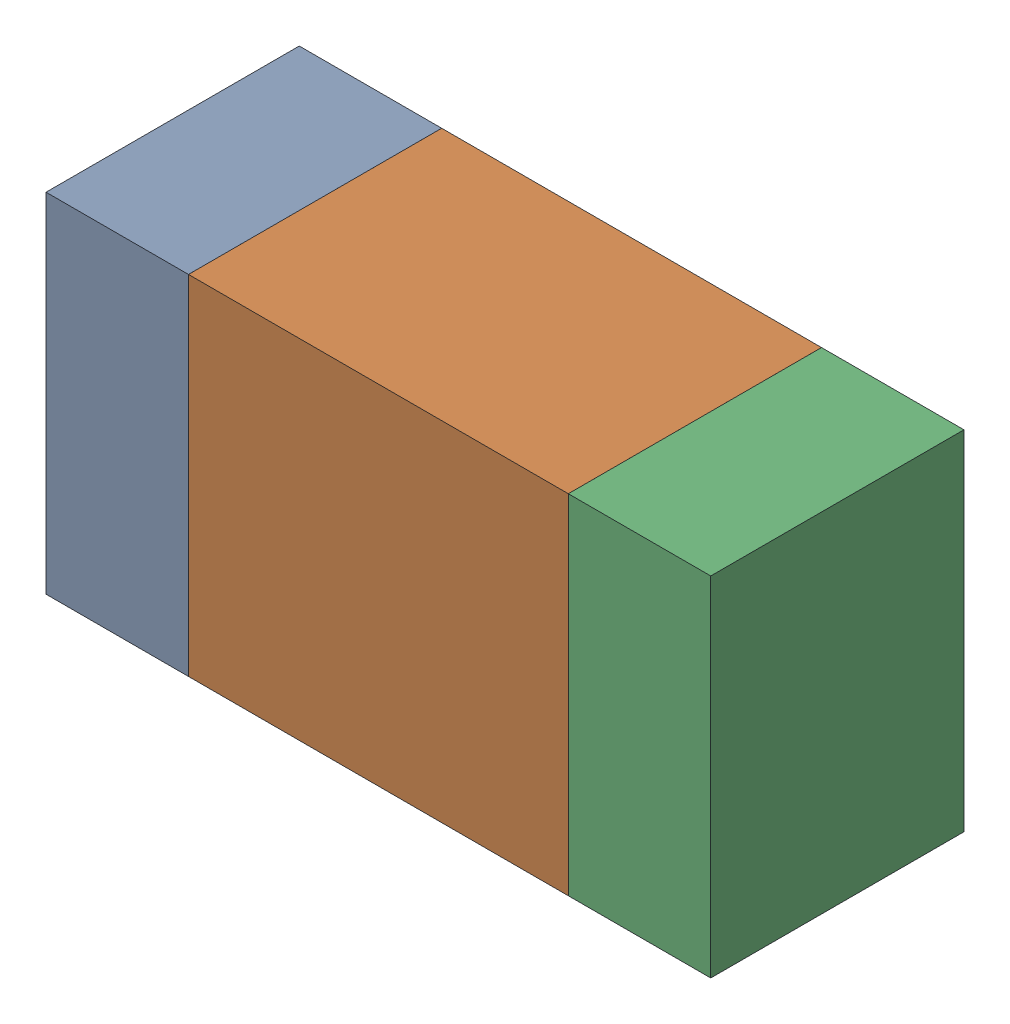
SolidWorks assembly R505_1PCB, configuration Default. Lengths in mm.
Overall size (1.05 0.55 0.4).
6 component instances, 2 part files, 0 mates.
Components (placement in the parent):
- 854785432-1: 854785432 [Default] at (156.2374 115.7499 0) size (0.22 0.55 0.4)
  - Extruded-1: Extruded [Default] at origin size (0.22 0.55 0.4)
- 854785568-1: 854785568 [Default] at (156.6499 115.7499 0) size (0.6 0.55 0.4)
  - Extruded_2-1: Extruded_2 [Default] at origin size (0.6 0.55 0.4)
- 854785432-2: 854785432 [Default] at (157.0624 115.7499 0) size (0.22 0.55 0.4)
  - Extruded-1: Extruded [Default] at origin size (0.22 0.55 0.4)
